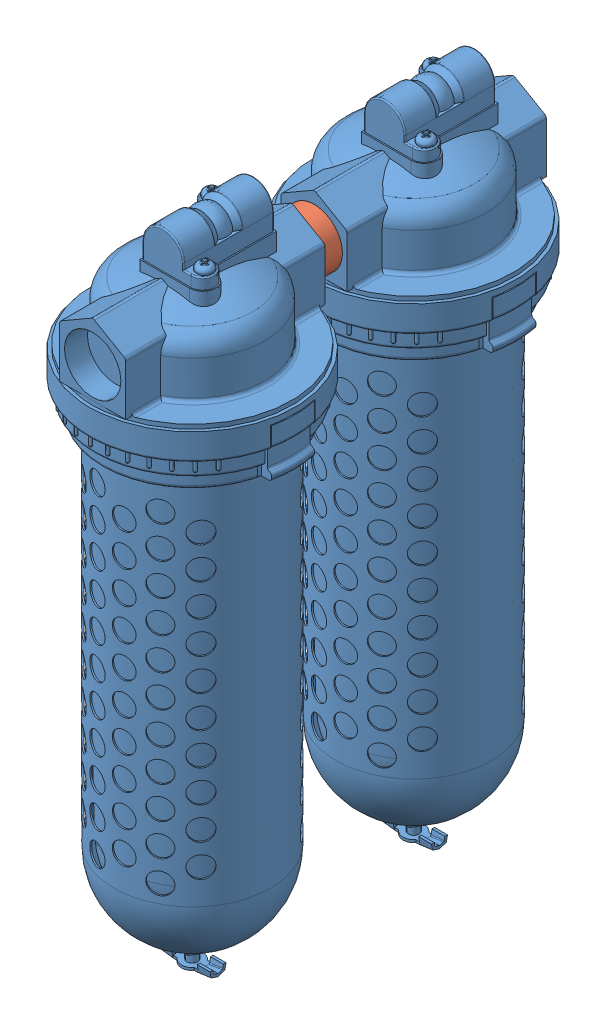
SolidWorks assembly ReadingTech_3P-150-P08-DCPi, configuration Default. Lengths in mm.
Overall size (121.86 385.36 252.73).
3 component instances, 2 part files, 2 mates.
Components (placement in the parent):
- ReadingTech_3P-150-P08-Pi-1: ReadingTech_3P-150-P08-Pi [Default] at (-33.0307 -218.1208 -1.2284) size (121.86 385.36 121.67)
- ReadingTech_3P-150-P08-Pi-2: ReadingTech_3P-150-P08-Pi [Default] at (-33.0307 -218.1208 -132.2924) size (121.86 385.36 121.67)
- ReadingTech- 90,150cfm_connector_1in-1: ReadingTech- 90,150cfm_connector_1in [Default] at (-33.0307 170.8802 -60.1564) x (1 0 0) z (0 1 0) size (33.4 13.21 33.4)
Mates (geometry in assembly coordinates):
- Coincident1: coincident anti-aligned: circle of ReadingTech_3P-150-P08-Pi-2; circle of ReadingTech- 90,150cfm_connector_1in-1
- Coincident2: coincident aligned: circle of ReadingTech_3P-150-P08-Pi-1; circle of ReadingTech- 90,150cfm_connector_1in-1
